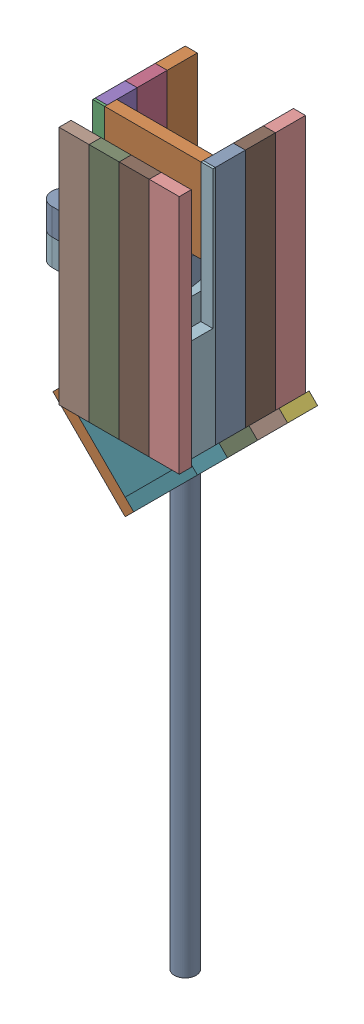
SolidWorks assembly Beach Hut Green, configuration Défaut. Lengths in mm.
Overall size (132.1 615 113.42).
11 component instances, 11 part files, 0 mates.
Components (placement in the parent):
- Beach hut - Matt-1: Beach hut - Matt [Défaut] at (-308.4913 -626.3682 198.8389) x (-0.87546 0 0.48329) z (-0.48329 0 -0.87546) size (18 500 18)
- Beach hut - Roof 2-1: Beach hut - Roof 2 [Défaut] at (-338.5433 -245.4583 161.3389) x (0 0 1) z (-0.707107 0.707107 0) size (100 10 85)
- Beach hut - Roof 1-1: Beach hut - Roof 1 [Défaut] at (-281.9748 -234.8517 161.3389) x (0 0 1) z (0.707107 0.707107 0) size (100 10 75)
- Beach hut - Wall 1-1: Beach hut - Wall 1 [Défaut] at (-258.4913 -116.3682 161.3389) x (0 0 1) z (0 -1 0) size (100 10 210)
- Beach hut - Wall 2-1: Beach hut - Wall 2 [Défaut] at (-358.4913 -116.3682 161.3389) x (0 0 1) z (0 -1 0) size (100 10 210)
- Beach hut - Wall back-1: Beach hut - Wall back [Défaut] at (-308.4913 -161.3682 148.8389) x (-1 0 0) z (0 0 1) size (80 100 10)
- Beach hut - Wall front-1: Beach hut - Wall front [Défaut] at (-308.4913 -126.3682 238.8389) x (-1 0 0) z (0 0 1) size (80 135 10)
- Beach hut - door-1: Beach hut - door [Défaut] at (-340.9913 -112.3682 258.8389) x (1 0 0) z (0 1 0) size (100 10 200)
- Beach hut - Ground-1: Beach hut - Ground [Défaut] at (-308.4913 -126.3682 198.8389) size (112 22 100)
- Beach hut - Door 2-1: Beach hut - Door 2 [Défaut] at (-369.4913 -82.3682 237.8389) x (0 0 1) z (1 0 0) size (103.42 22 106)
- Beach hut - Wall 3-1: Beach hut - Wall 3 [Défaut] at (-308.4913 -81.3682 215.8389) size (80 70 10)
